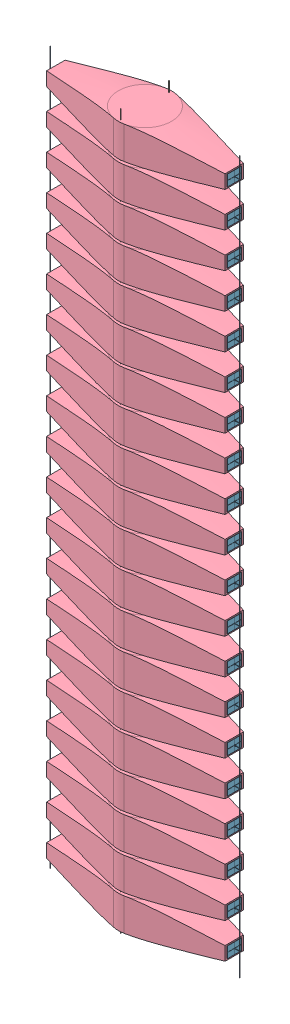
SolidWorks assembly String, configuration 默认. Lengths in mm.
Overall size (500 1325.9 125.56).
120 component instances, 5 part files, 13 mates.
Components (placement in the parent):
- BEGeDet-1: BEGeDet [默认] at (2.9686 -23.0613 80) size (80 40 80)
- InnerShell-IV-1: InnerShell-IV [默认] at (2.9686 -23.1113 80) x (0.656103 0 0.754671) z (-0.754671 0 0.656103) size (89 50 89)
- Electronics-1: Electronics [默认] at (2.9686 -48.2113 80) x (-1 0 0) z (0 0 -1) size (21.21 85 89.7)
- OuterShell-IV-2: OuterShell-IV [默认] at (2.9686 -24.1113 80) size (500 60 98)
- SiPMArray-IV-1: SiPMArray-IV [默认] at (167.9686 -24.1113 80) size (10.4 81 26.4)
- SiPMArray-IV-2: SiPMArray-IV [默认] at (-161.6528 -24.1113 80) x (-1 0 0) z (0 0 -1) size (10.4 81 26.4)
- SiPMArray-IV-3: SiPMArray-IV [默认] at (167.9686 40.8887 80) size (10.4 81 26.4)
- SiPMArray-IV-4: SiPMArray-IV [默认] at (167.9686 105.8887 80) size (10.4 81 26.4)
- SiPMArray-IV-5: SiPMArray-IV [默认] at (167.9686 170.8887 80) size (10.4 81 26.4)
- SiPMArray-IV-6: SiPMArray-IV [默认] at (167.9686 235.8887 80) size (10.4 81 26.4)
- SiPMArray-IV-7: SiPMArray-IV [默认] at (167.9686 300.8887 80) size (10.4 81 26.4)
- SiPMArray-IV-8: SiPMArray-IV [默认] at (167.9686 365.8887 80) size (10.4 81 26.4)
- SiPMArray-IV-9: SiPMArray-IV [默认] at (167.9686 430.8887 80) size (10.4 81 26.4)
- SiPMArray-IV-10: SiPMArray-IV [默认] at (167.9686 495.8887 80) size (10.4 81 26.4)
- SiPMArray-IV-11: SiPMArray-IV [默认] at (167.9686 560.8887 80) size (10.4 81 26.4)
- SiPMArray-IV-12: SiPMArray-IV [默认] at (167.9686 625.8887 80) size (10.4 81 26.4)
- SiPMArray-IV-13: SiPMArray-IV [默认] at (167.9686 690.8887 80) size (10.4 81 26.4)
- SiPMArray-IV-14: SiPMArray-IV [默认] at (167.9686 755.8887 80) size (10.4 81 26.4)
- SiPMArray-IV-15: SiPMArray-IV [默认] at (167.9686 820.8887 80) size (10.4 81 26.4)
- SiPMArray-IV-16: SiPMArray-IV [默认] at (167.9686 885.8887 80) size (10.4 81 26.4)
- SiPMArray-IV-17: SiPMArray-IV [默认] at (167.9686 950.8887 80) size (10.4 81 26.4)
- SiPMArray-IV-18: SiPMArray-IV [默认] at (167.9686 1015.8887 80) size (10.4 81 26.4)
- SiPMArray-IV-19: SiPMArray-IV [默认] at (167.9686 1080.8887 80) size (10.4 81 26.4)
- SiPMArray-IV-20: SiPMArray-IV [默认] at (167.9686 1145.8887 80) size (10.4 81 26.4)
- SiPMArray-IV-21: SiPMArray-IV [默认] at (167.9686 1210.8887 80) size (10.4 81 26.4)
- SiPMArray-IV-22: SiPMArray-IV [默认] at (-161.6528 40.8887 80) x (-1 0 0) z (0 0 -1) size (10.4 81 26.4)
- SiPMArray-IV-23: SiPMArray-IV [默认] at (-161.6528 105.8887 80) x (-1 0 0) z (0 0 -1) size (10.4 81 26.4)
- SiPMArray-IV-24: SiPMArray-IV [默认] at (-161.6528 170.8887 80) x (-1 0 0) z (0 0 -1) size (10.4 81 26.4)
- SiPMArray-IV-25: SiPMArray-IV [默认] at (-161.6528 235.8887 80) x (-1 0 0) z (0 0 -1) size (10.4 81 26.4)
- SiPMArray-IV-26: SiPMArray-IV [默认] at (-161.6528 300.8887 80) x (-1 0 0) z (0 0 -1) size (10.4 81 26.4)
- SiPMArray-IV-27: SiPMArray-IV [默认] at (-161.6528 365.8887 80) x (-1 0 0) z (0 0 -1) size (10.4 81 26.4)
- SiPMArray-IV-28: SiPMArray-IV [默认] at (-161.6528 430.8887 80) x (-1 0 0) z (0 0 -1) size (10.4 81 26.4)
- SiPMArray-IV-29: SiPMArray-IV [默认] at (-161.6528 495.8887 80) x (-1 0 0) z (0 0 -1) size (10.4 81 26.4)
- SiPMArray-IV-30: SiPMArray-IV [默认] at (-161.6528 560.8887 80) x (-1 0 0) z (0 0 -1) size (10.4 81 26.4)
- SiPMArray-IV-31: SiPMArray-IV [默认] at (-161.6528 625.8887 80) x (-1 0 0) z (0 0 -1) size (10.4 81 26.4)
- SiPMArray-IV-32: SiPMArray-IV [默认] at (-161.6528 690.8887 80) x (-1 0 0) z (0 0 -1) size (10.4 81 26.4)
- SiPMArray-IV-33: SiPMArray-IV [默认] at (-161.6528 755.8887 80) x (-1 0 0) z (0 0 -1) size (10.4 81 26.4)
- SiPMArray-IV-34: SiPMArray-IV [默认] at (-161.6528 820.8887 80) x (-1 0 0) z (0 0 -1) size (10.4 81 26.4)
- SiPMArray-IV-35: SiPMArray-IV [默认] at (-161.6528 885.8887 80) x (-1 0 0) z (0 0 -1) size (10.4 81 26.4)
- SiPMArray-IV-36: SiPMArray-IV [默认] at (-161.6528 950.8887 80) x (-1 0 0) z (0 0 -1) size (10.4 81 26.4)
- SiPMArray-IV-37: SiPMArray-IV [默认] at (-161.6528 1015.8887 80) x (-1 0 0) z (0 0 -1) size (10.4 81 26.4)
- SiPMArray-IV-38: SiPMArray-IV [默认] at (-161.6528 1080.8887 80) x (-1 0 0) z (0 0 -1) size (10.4 81 26.4)
- SiPMArray-IV-39: SiPMArray-IV [默认] at (-161.6528 1145.8887 80) x (-1 0 0) z (0 0 -1) size (10.4 81 26.4)
- SiPMArray-IV-40: SiPMArray-IV [默认] at (-161.6528 1210.8887 80) x (-1 0 0) z (0 0 -1) size (10.4 81 26.4)
- InnerShell-IV-2: InnerShell-IV [默认] at (2.9686 41.8887 80) x (0.656103 0 0.754671) z (-0.754671 0 0.656103) size (89 50 89)
- InnerShell-IV-3: InnerShell-IV [默认] at (2.9686 106.8887 80) x (0.656103 0 0.754671) z (-0.754671 0 0.656103) size (89 50 89)
- InnerShell-IV-4: InnerShell-IV [默认] at (2.9686 171.8887 80) x (0.656103 0 0.754671) z (-0.754671 0 0.656103) size (89 50 89)
- InnerShell-IV-5: InnerShell-IV [默认] at (2.9686 236.8887 80) x (0.656103 0 0.754671) z (-0.754671 0 0.656103) size (89 50 89)
- InnerShell-IV-6: InnerShell-IV [默认] at (2.9686 301.8887 80) x (0.656103 0 0.754671) z (-0.754671 0 0.656103) size (89 50 89)
- InnerShell-IV-7: InnerShell-IV [默认] at (2.9686 366.8887 80) x (0.656103 0 0.754671) z (-0.754671 0 0.656103) size (89 50 89)
- InnerShell-IV-8: InnerShell-IV [默认] at (2.9686 431.8887 80) x (0.656103 0 0.754671) z (-0.754671 0 0.656103) size (89 50 89)
- InnerShell-IV-9: InnerShell-IV [默认] at (2.9686 496.8887 80) x (0.656103 0 0.754671) z (-0.754671 0 0.656103) size (89 50 89)
- InnerShell-IV-10: InnerShell-IV [默认] at (2.9686 561.8887 80) x (0.656103 0 0.754671) z (-0.754671 0 0.656103) size (89 50 89)
- InnerShell-IV-11: InnerShell-IV [默认] at (2.9686 626.8887 80) x (0.656103 0 0.754671) z (-0.754671 0 0.656103) size (89 50 89)
- InnerShell-IV-12: InnerShell-IV [默认] at (2.9686 691.8887 80) x (0.656103 0 0.754671) z (-0.754671 0 0.656103) size (89 50 89)
- InnerShell-IV-13: InnerShell-IV [默认] at (2.9686 756.8887 80) x (0.656103 0 0.754671) z (-0.754671 0 0.656103) size (89 50 89)
- InnerShell-IV-14: InnerShell-IV [默认] at (2.9686 821.8887 80) x (0.656103 0 0.754671) z (-0.754671 0 0.656103) size (89 50 89)
- InnerShell-IV-15: InnerShell-IV [默认] at (2.9686 886.8887 80) x (0.656103 0 0.754671) z (-0.754671 0 0.656103) size (89 50 89)
- InnerShell-IV-16: InnerShell-IV [默认] at (2.9686 951.8887 80) x (0.656103 0 0.754671) z (-0.754671 0 0.656103) size (89 50 89)
- InnerShell-IV-17: InnerShell-IV [默认] at (2.9686 1016.8887 80) x (0.656103 0 0.754671) z (-0.754671 0 0.656103) size (89 50 89)
- InnerShell-IV-18: InnerShell-IV [默认] at (2.9686 1081.8887 80) x (0.656103 0 0.754671) z (-0.754671 0 0.656103) size (89 50 89)
- InnerShell-IV-19: InnerShell-IV [默认] at (2.9686 1146.8887 80) x (0.656103 0 0.754671) z (-0.754671 0 0.656103) size (89 50 89)
- InnerShell-IV-20: InnerShell-IV [默认] at (2.9686 1211.8887 80) x (0.656103 0 0.754671) z (-0.754671 0 0.656103) size (89 50 89)
- BEGeDet-2: BEGeDet [默认] at (2.9686 41.9387 80) size (80 40 80)
- BEGeDet-3: BEGeDet [默认] at (2.9686 106.9387 80) size (80 40 80)
- BEGeDet-4: BEGeDet [默认] at (2.9686 171.9387 80) size (80 40 80)
- BEGeDet-5: BEGeDet [默认] at (2.9686 236.9387 80) size (80 40 80)
- BEGeDet-6: BEGeDet [默认] at (2.9686 301.9387 80) size (80 40 80)
- BEGeDet-7: BEGeDet [默认] at (2.9686 366.9387 80) size (80 40 80)
- BEGeDet-8: BEGeDet [默认] at (2.9686 431.9387 80) size (80 40 80)
- BEGeDet-9: BEGeDet [默认] at (2.9686 496.9387 80) size (80 40 80)
- BEGeDet-10: BEGeDet [默认] at (2.9686 561.9387 80) size (80 40 80)
- BEGeDet-11: BEGeDet [默认] at (2.9686 626.9387 80) size (80 40 80)
- BEGeDet-12: BEGeDet [默认] at (2.9686 691.9387 80) size (80 40 80)
- BEGeDet-13: BEGeDet [默认] at (2.9686 756.9387 80) size (80 40 80)
- BEGeDet-14: BEGeDet [默认] at (2.9686 821.9387 80) size (80 40 80)
- BEGeDet-15: BEGeDet [默认] at (2.9686 886.9387 80) size (80 40 80)
- BEGeDet-16: BEGeDet [默认] at (2.9686 951.9387 80) size (80 40 80)
- BEGeDet-17: BEGeDet [默认] at (2.9686 1016.9387 80) size (80 40 80)
- BEGeDet-18: BEGeDet [默认] at (2.9686 1081.9387 80) size (80 40 80)
- BEGeDet-19: BEGeDet [默认] at (2.9686 1146.9387 80) size (80 40 80)
- BEGeDet-20: BEGeDet [默认] at (2.9686 1211.9387 80) size (80 40 80)
- Electronics-2: Electronics [默认] at (2.9686 16.7887 80) x (-1 0 0) z (0 0 -1) size (21.21 85 89.7)
- Electronics-3: Electronics [默认] at (2.9686 81.7887 80) x (-1 0 0) z (0 0 -1) size (21.21 85 89.7)
- Electronics-4: Electronics [默认] at (2.9686 146.7887 80) x (-1 0 0) z (0 0 -1) size (21.21 85 89.7)
- Electronics-5: Electronics [默认] at (2.9686 211.7887 80) x (-1 0 0) z (0 0 -1) size (21.21 85 89.7)
- Electronics-6: Electronics [默认] at (2.9686 276.7887 80) x (-1 0 0) z (0 0 -1) size (21.21 85 89.7)
- Electronics-7: Electronics [默认] at (2.9686 341.7887 80) x (-1 0 0) z (0 0 -1) size (21.21 85 89.7)
- Electronics-8: Electronics [默认] at (2.9686 406.7887 80) x (-1 0 0) z (0 0 -1) size (21.21 85 89.7)
- Electronics-9: Electronics [默认] at (2.9686 471.7887 80) x (-1 0 0) z (0 0 -1) size (21.21 85 89.7)
- Electronics-10: Electronics [默认] at (2.9686 536.7887 80) x (-1 0 0) z (0 0 -1) size (21.21 85 89.7)
- Electronics-11: Electronics [默认] at (2.9686 601.7887 80) x (-1 0 0) z (0 0 -1) size (21.21 85 89.7)
- Electronics-12: Electronics [默认] at (2.9686 666.7887 80) x (-1 0 0) z (0 0 -1) size (21.21 85 89.7)
- Electronics-13: Electronics [默认] at (2.9686 731.7887 80) x (-1 0 0) z (0 0 -1) size (21.21 85 89.7)
- Electronics-14: Electronics [默认] at (2.9686 796.7887 80) x (-1 0 0) z (0 0 -1) size (21.21 85 89.7)
- Electronics-15: Electronics [默认] at (2.9686 861.7887 80) x (-1 0 0) z (0 0 -1) size (21.21 85 89.7)
- Electronics-16: Electronics [默认] at (2.9686 926.7887 80) x (-1 0 0) z (0 0 -1) size (21.21 85 89.7)
- Electronics-17: Electronics [默认] at (2.9686 991.7887 80) x (-1 0 0) z (0 0 -1) size (21.21 85 89.7)
- Electronics-18: Electronics [默认] at (2.9686 1056.7887 80) x (-1 0 0) z (0 0 -1) size (21.21 85 89.7)
- Electronics-19: Electronics [默认] at (2.9686 1121.7887 80) x (-1 0 0) z (0 0 -1) size (21.21 85 89.7)
- Electronics-20: Electronics [默认] at (2.9686 1186.7887 80) x (-1 0 0) z (0 0 -1) size (21.21 85 89.7)
- OuterShell-IV-3: OuterShell-IV [默认] at (2.9686 40.8887 80) size (500 60 98)
- OuterShell-IV-4: OuterShell-IV [默认] at (2.9686 105.8887 80) size (500 60 98)
- OuterShell-IV-5: OuterShell-IV [默认] at (2.9686 170.8887 80) size (500 60 98)
- OuterShell-IV-6: OuterShell-IV [默认] at (2.9686 235.8887 80) size (500 60 98)
- OuterShell-IV-7: OuterShell-IV [默认] at (2.9686 300.8887 80) size (500 60 98)
- OuterShell-IV-8: OuterShell-IV [默认] at (2.9686 365.8887 80) size (500 60 98)
- OuterShell-IV-9: OuterShell-IV [默认] at (2.9686 430.8887 80) size (500 60 98)
- OuterShell-IV-10: OuterShell-IV [默认] at (2.9686 495.8887 80) size (500 60 98)
- OuterShell-IV-11: OuterShell-IV [默认] at (2.9686 560.8887 80) size (500 60 98)
- OuterShell-IV-12: OuterShell-IV [默认] at (2.9686 625.8887 80) size (500 60 98)
- OuterShell-IV-13: OuterShell-IV [默认] at (2.9686 690.8887 80) size (500 60 98)
- OuterShell-IV-14: OuterShell-IV [默认] at (2.9686 755.8887 80) size (500 60 98)
- OuterShell-IV-15: OuterShell-IV [默认] at (2.9686 820.8887 80) size (500 60 98)
- OuterShell-IV-16: OuterShell-IV [默认] at (2.9686 885.8887 80) size (500 60 98)
- OuterShell-IV-17: OuterShell-IV [默认] at (2.9686 950.8887 80) size (500 60 98)
- OuterShell-IV-18: OuterShell-IV [默认] at (2.9686 1015.8887 80) size (500 60 98)
- OuterShell-IV-19: OuterShell-IV [默认] at (2.9686 1080.8887 80) size (500 60 98)
- OuterShell-IV-20: OuterShell-IV [默认] at (2.9686 1145.8887 80) size (500 60 98)
- OuterShell-IV-21: OuterShell-IV [默认] at (2.9686 1210.8887 80) size (500 60 98)
Mates (geometry in assembly coordinates):
- 重合1: coincident anti-aligned: plane of BEGeDet-1 through (2.9686 -3.0613 80) normal (0 1 0); plane of InnerShell-IV-1 through (2.9686 -3.0613 80) normal (0 -1 0)
- 同心1: concentric aligned: circle of BEGeDet-1; circle of InnerShell-IV-1
- 同心14: concentric anti-aligned: circle of BEGeDet-1; circle of Electronics-1
- 重合10: coincident anti-aligned: plane of InnerShell-IV-1 through (2.9686 -48.1113 80) normal (0 -1 0); plane of Electronics-1 through (2.9686 -48.1113 60.201) normal (0 1 0)
- 重合11: coincident anti-aligned: circle of InnerShell-IV-1; plane of OuterShell-IV-2 through (2.9686 1.8887 80) normal (0 -1 0)
- 同心15: concentric aligned: circle of InnerShell-IV-1; circle of OuterShell-IV-2
- 平行1: parallel aligned: line of BEGeDet-1 through (2.9686 -43.0613 80) axis (1 0 0); line of OuterShell-IV-2 through (2.9686 -24.1113 80) axis (1 0 0)
- 垂直1: perpendicular: line of Electronics-1 through (3.1686 -48.2113 60.401) axis (0 0 -1); line of OuterShell-IV-2 through (2.9686 -24.1113 80) axis (1 0 0)
- 重合14: coincident anti-aligned: plane of OuterShell-IV-2 through (167.9686 -54.1121 63.0105) normal (1 0 0); plane of SiPMArray-IV-1 through (167.9686 -24.1113 80) normal (-1 0 0)
- 重合15: coincident: point of OuterShell-IV-2; point of SiPMArray-IV-1
- 重合18: coincident anti-aligned: plane of OuterShell-IV-2 through (-161.6528 -54.1121 97.0652) normal (-1 0 0); plane of SiPMArray-IV-2 through (-161.6528 -24.1113 80) normal (1 0 0)
- 重合19: coincident: point of OuterShell-IV-2; point of SiPMArray-IV-2
- 平行4: parallel anti-aligned: line of OuterShell-IV-2 through (-161.6528 -36.7228 62.9348) axis (0 1 0); line of SiPMArray-IV-2 through (-162.1528 -13.9113 66.8) axis (0 -1 0)
